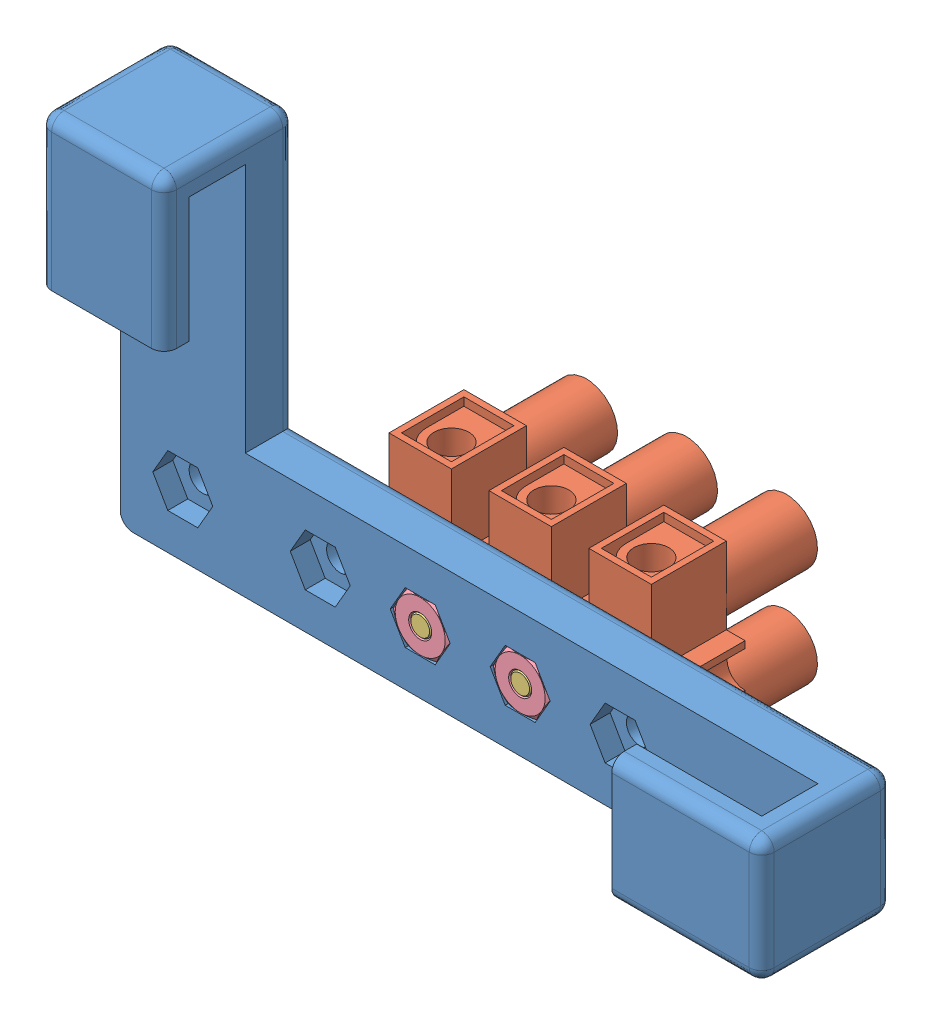
SolidWorks assembly alimentation, configuration Défaut. Lengths in mm.
Overall size (57.83 35.15 23.8).
6 component instances, 4 part files, 13 mates.
Components (placement in the parent):
- attache-domino-1: attache-domino [Défaut] at (-3.5647 -8.4018 55.5822) size (57.83 32 10.5)
- Domino-6A-1: Domino-6A [Défaut] at (-9.5647 -3.4018 48.5822) x (1 0 0) z (0 1 0) size (24 13.3 16.3)
- vis-chc-1: vis-chc [Vis CHC M2x10] at (-5.5647 -3.4018 45.5822) x (0.376147 0.92656 0) z (-0.92656 0.376147 0) size (3.8 12 3.8)
- vis-chc-2: vis-chc [Vis CHC M2x10] at (2.4353 -3.4018 45.5822) x (0.964775 0.263078 0) z (-0.263078 0.964775 0) size (3.8 12 3.8)
- ecrou-h-1: ecrou-h [6007 HU M2] at (-5.5647 -3.4018 55.5822) x (0.866025 0.5 0) z (0.5 -0.866025 0) size (4 1.6 4.62)
- ecrou-h-2: ecrou-h [6007 HU M2] at (2.4353 -3.4018 55.5822) x (0.866025 -0.5 0) z (-0.5 -0.866025 0) size (4 1.6 4.62)
Mates (geometry in assembly coordinates):
- Coïncidente1: coincident anti-aligned: plane of attache-domino-1 through (28.2675 1.5982 51.5822) normal (0 0 -1); plane of Domino-6A-1 through (-12.0647 4.7482 51.5822) normal (0 0 1)
- Coaxiale1: concentric aligned: cylinder of Domino-6A-1 through (-5.5647 -3.4018 51.5822) axis (0 0 -1) radius 1.45; cylinder of vis-chc-1 through (-5.5647 -3.4018 55.5822) axis (0 0 -1) radius 1
- Coaxiale2: concentric aligned: cylinder of attache-domino-1 through (-5.5647 -3.4018 62.0832) axis (0 0 -1) radius 1.1; cylinder of Domino-6A-1 through (-5.5647 -3.4018 51.5822) axis (0 0 -1) radius 1.45
- Coaxiale3: concentric aligned: cylinder of attache-domino-1 through (2.4353 -3.4018 62.0832) axis (0 0 -1) radius 1.1; cylinder of Domino-6A-1 through (2.4353 -3.4018 51.5822) axis (0 0 -1) radius 1.45
- Coïncidente2: coincident anti-aligned: plane of Domino-6A-1 through (-12.0647 4.7482 45.5822) normal (0 0 -1); plane of vis-chc-1 through (-5.5647 -3.4018 45.5822) normal (0 0 1)
- Coaxiale4: concentric aligned: cylinder of Domino-6A-1 through (2.4353 -3.4018 51.5822) axis (0 0 -1) radius 1.45; cylinder of vis-chc-2 through (2.4353 -3.4018 55.5822) axis (0 0 -1) radius 1
- Coïncidente3: coincident anti-aligned: plane of Domino-6A-1 through (-12.0647 4.7482 45.5822) normal (0 0 -1); plane of vis-chc-2 through (2.4353 -3.4018 45.5822) normal (0 0 1)
- Coaxiale5: concentric anti-aligned: cylinder of vis-chc-1 through (-5.5647 -3.4018 55.5822) axis (0 0 -1) radius 1; cylinder of ecrou-h-1 through (-5.5647 -3.4018 53.9822) axis (0 0 1) radius 0.7835
- Coïncidente4: coincident anti-aligned: plane of attache-domino-1 through (-3.5647 -8.4018 53.9822) normal (0 0 1); plane of ecrou-h-1 through (-4.41 -1.4018 53.9822) normal (0 0 -1)
- Parallèle1: parallel anti-aligned: plane of attache-domino-1 through (-6.7647 -1.3233 53.9822) normal (0.866025 -0.5 0); plane of ecrou-h-1 through (-6.7194 -1.4018 53.9822) normal (-0.866025 0.5 0)
- Coaxiale6: concentric anti-aligned: cylinder of vis-chc-2 through (2.4353 -3.4018 55.5822) axis (0 0 -1) radius 1; cylinder of ecrou-h-2 through (2.4353 -3.4018 53.9822) axis (0 0 1) radius 0.7835
- Coïncidente6: coincident anti-aligned: plane of attache-domino-1 through (-3.5647 -8.4018 53.9822) normal (0 0 1); plane of ecrou-h-2 through (4.7447 -3.4018 53.9822) normal (0 0 -1)
- Parallèle2: parallel anti-aligned: plane of attache-domino-1 through (1.2353 -1.3233 53.9822) normal (0.866025 -0.5 0); plane of ecrou-h-2 through (1.2806 -1.4018 53.9822) normal (-0.866025 0.5 0)
